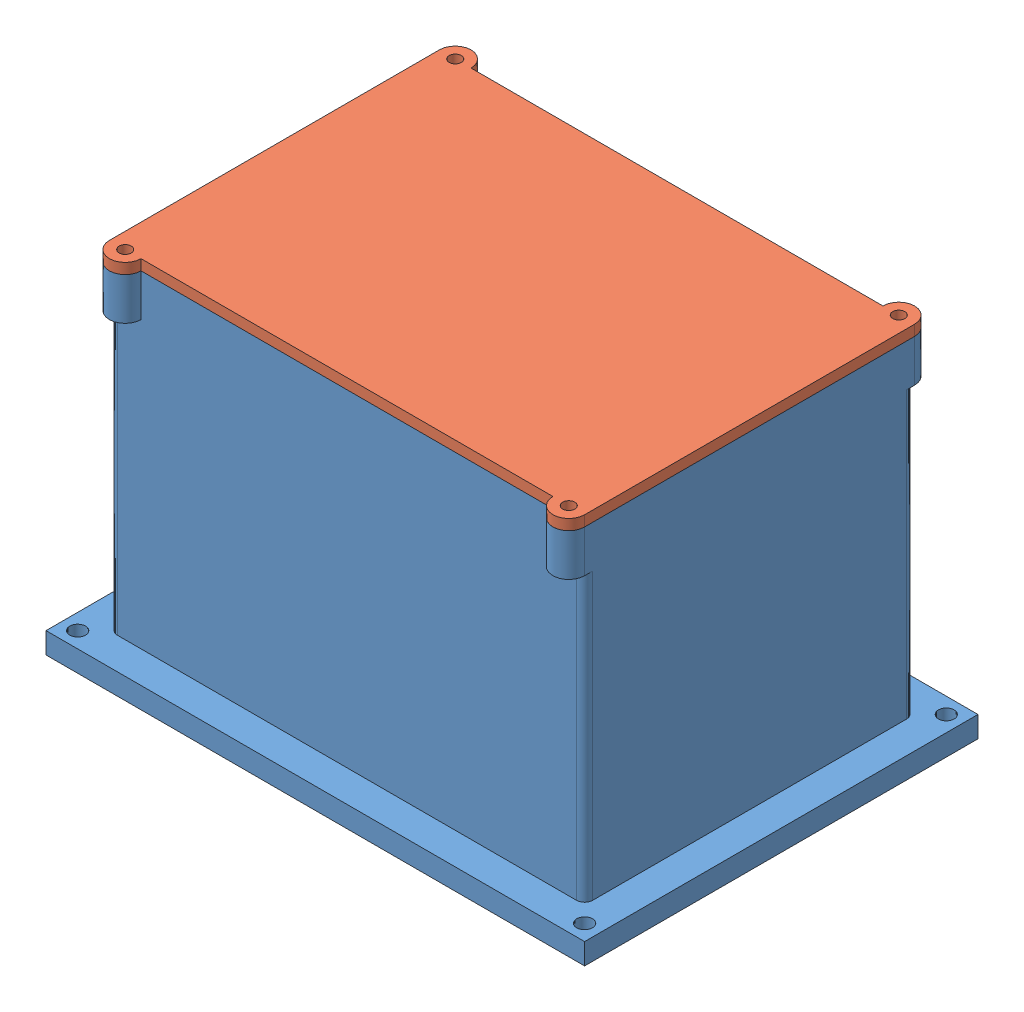
SolidWorks assembly XBee Housing, configuration Default. Lengths in mm.
Overall size (102 68 74.5).
2 component instances, 2 part files, 3 mates.
Components (placement in the parent):
- XBee Board-1: XBee Board [Default] at (-11.736 20.0575 113.9231) size (102 66 74.5)
- XBee Top Cover-1: XBee Top Cover [Default] at (-11.736 86.0575 113.9231) size (90 4 68.5)
Mates (geometry in assembly coordinates):
- Concentric1: concentric: cylinder of XBee Board-1 through (-8.736 80.0575 113.9231) axis (0 1 0) radius 1.15; cylinder of XBee Top Cover-1 through (-8.736 86.0575 113.9231) axis (0 1 0) radius 1.15
- Concentric2: concentric: cylinder of XBee Board-1 through (75.264 80.0575 51.4231) axis (0 1 0) radius 1.15; cylinder of XBee Top Cover-1 through (75.264 86.0575 51.4231) axis (0 1 0) radius 1.15
- Coincident1: coincident: plane of XBee Board-1 through (-11.736 86.0575 113.9231) normal (0 1 0); plane of XBee Top Cover-1 through (-8.736 86.0575 113.9231) normal (0 -1 0)
